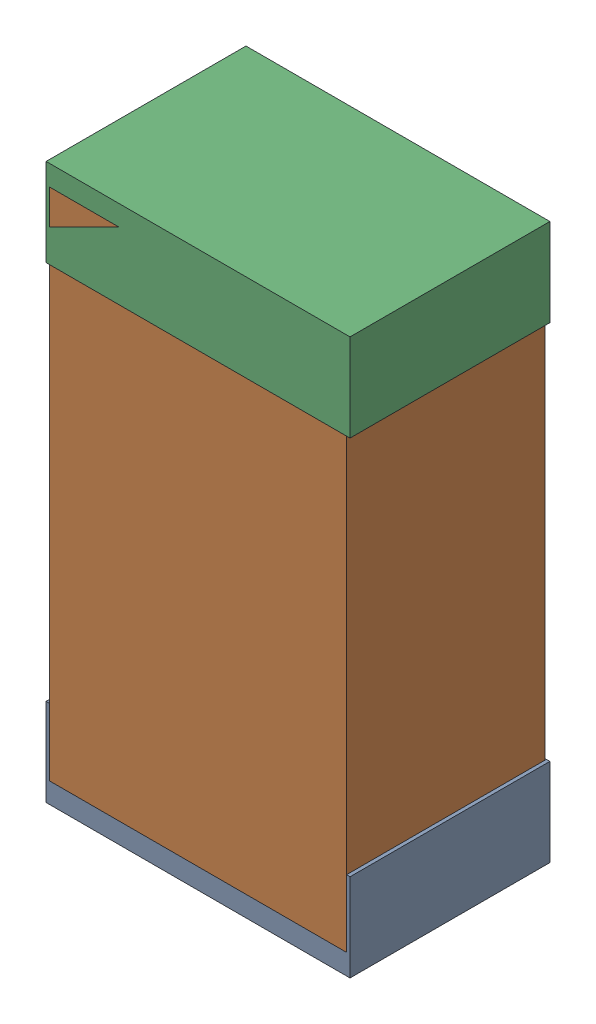
SolidWorks assembly R18Kanaloa_v2.0.0_Motor, configuration Default. Lengths in mm.
Overall size (1.3 2.38 0.85).
6 component instances, 2 part files, 0 mates.
Components (placement in the parent):
- 330415056-1: 330415056 [Default] at (126.238 68.85 -1.9574) size (1.3 0.38 0.85)
  - Extruded_2-1: Extruded_2 [Default] at origin size (1.3 0.38 0.85)
- 334787376-1: 334787376 [Default] at (126.238 69.85 -1.9524) size (1.27 2.2 0.85)
  - Extruded_16-1: Extruded_16 [Default] at origin size (1.27 2.2 0.85)
- 330415056-2: 330415056 [Default] at (126.238 70.85 -1.9574) size (1.3 0.38 0.85)
  - Extruded_2-1: Extruded_2 [Default] at origin size (1.3 0.38 0.85)
